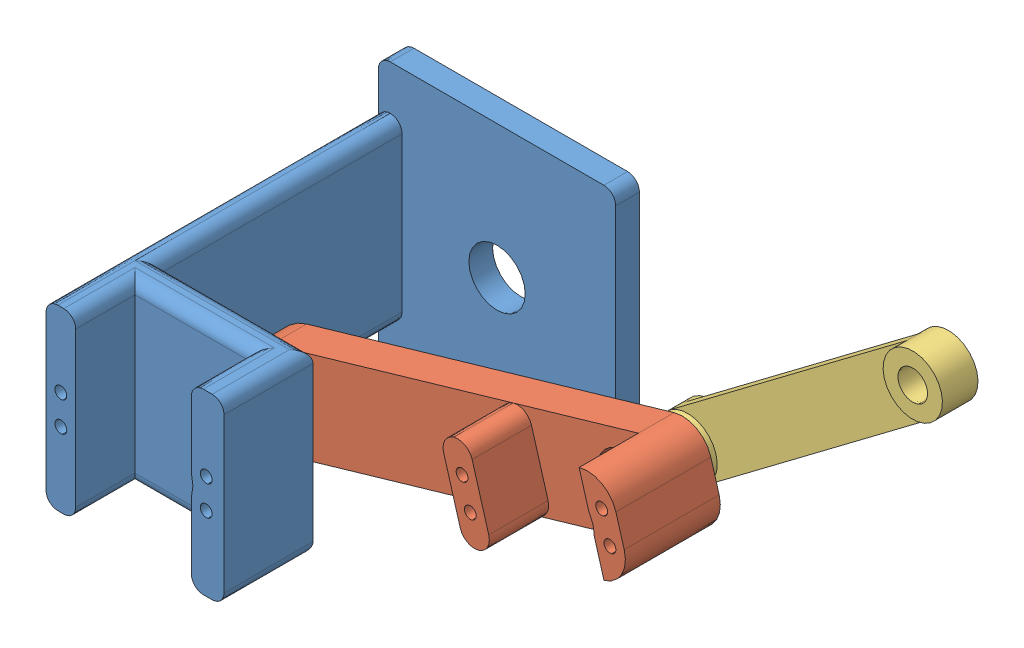
SolidWorks assembly robot, configuration Default. Lengths in mm.
Overall size (249.1 152.71 120).
3 component instances, 3 part files, 4 mates.
Components (placement in the parent):
- link1-1: link1 [Default] at origin size (80 90 120)
- link2-1: link2 [Default] at (44.194 15.5982 -32) x (0.960117 0.279598 0) z (0.279598 -0.960117 0) size (154 32 30)
- link3-1: link3 [Default] at (149.1984 71.5399 -37) x (0.798822 0.601567 0) z (-0.601567 0.798822 0) size (120 12 20)
Mates (geometry in assembly coordinates):
- Concentric1: concentric aligned: cylinder of link1-1 through (40 30 0.001) axis (0 0 -1) radius 9.5; cylinder of link2-1 through (40 30 -20) axis (0 0 -1) radius 2.95
- Distance1: distance = 10 mm anti-aligned: plane of link1-1 through (8 60 -10) normal (0 0 -1); plane of link2-1 through (40 30 -20) normal (0 0 1)
- Concentric2: concentric anti-aligned: cylinder of link2-1 through (155.2141 63.5517 -20) axis (0 0 -1) radius 9.5; cylinder of link3-1 through (155.2141 63.5517 -49) axis (0 0 1) radius 2.95
- Distance2: distance = 5 mm anti-aligned: plane of link2-1 through (40 30 -32) normal (0 0 -1); plane of link3-1 through (155.2141 63.5517 -37) normal (0 0 1)
